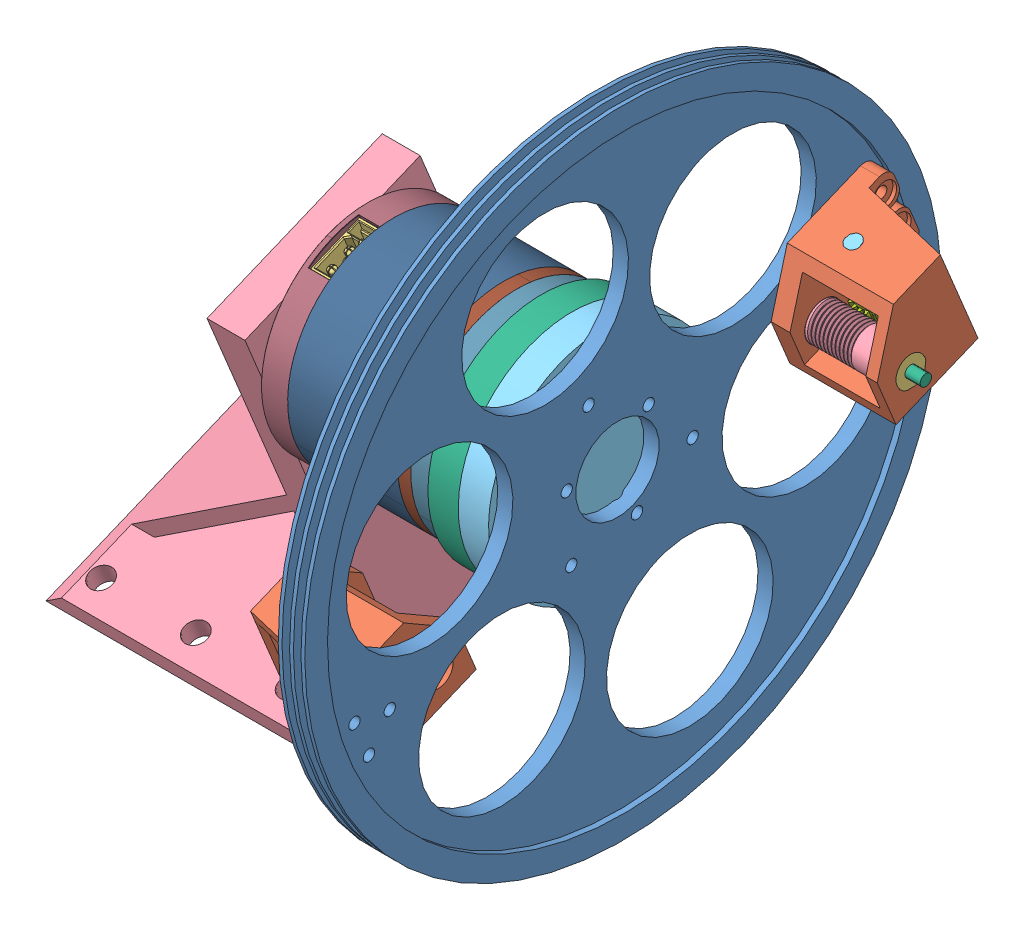
SolidWorks assembly 电机测试组件, configuration 默认. Lengths in mm.
Overall size (174 219.42 219.42).
54 component instances, 24 part files, 15 mates.
Components (placement in the parent):
- 轮组2.0-1: 轮组2.0 [默认] at (56.4404 123.864 309.1516) x (0 -0.381849 0.924225) z (0 0.924225 0.381849) size (168 7.5 168)
- 装配体-1: 装配体 [默认] at (78.4555 112.6983 239.544) x (1 0 0) z (0 0.924225 0.381849) size (32 33.9 26)
  - box - 0-1: box - 0 [默认] at (-1.5151 4.9306 23.8992) size (28 33.9 26)
  - bearing-1: bearing [默认] at (-12.3151 -9.9694 28.8992) x (0 0 1) z (-1 0 0) size (9 9 3)
  - bearing-2: bearing [默认] at (9.2849 -9.9694 28.8992) x (0 -0.428044 -0.903758) z (1 0 0) size (9 9 3)
  - 零件2-1: 零件2 [默认] at (-11.5151 -9.9694 28.8992) x (1 0 0) z (0 -0.101118 0.994874) size (20 9.82 9.8)
  - zhou1-1: zhou1 [默认] at (-5.5151 -0.5694 20.8992) x (1 0 0) z (0 -1 0) size (4 26 4)
  - zhou2-1: zhou2 [默认] at (-14.5151 -9.9694 28.8992) x (0 0 -1) z (1 0 0) size (3 3 30)
  - gear-1: gear [默认] at (-5.5151 -0.5694 31.3992) x (0 0 -1) z (0.913862 -0.406024 0) size (12 10.93 10.93)
  - 1-1: 1 [默认] at (-5.5151 -0.5694 23.8992) x (0.998523 -0.054325 0) z (0 0 1) size (9 9 2.5)
  - 2-1: 2 [默认] at (-5.5151 -0.5694 38.3992) x (0.999989 0.004731 0) z (0 0 1) size (9 9 5.5)
- 装配体-2: 装配体 [默认] at (41.4254 66.8234 350.5792) x (-1 0 0) z (0 0.924225 0.381849) size (32 33.9 26)
  - box - 0-1: box - 0 [默认] at (-1.5151 4.9306 23.8992) size (28 33.9 26)
  - bearing-1: bearing [默认] at (-12.3151 -9.9694 28.8992) x (0 0 1) z (-1 0 0) size (9 9 3)
  - bearing-2: bearing [默认] at (9.2849 -9.9694 28.8992) x (0 -0.428044 -0.903758) z (1 0 0) size (9 9 3)
  - 零件2-1: 零件2 [默认] at (-11.5151 -9.9694 28.8992) x (1 0 0) z (0 -0.101118 0.994874) size (20 9.82 9.8)
  - zhou1-1: zhou1 [默认] at (-5.5151 -0.5694 20.8992) x (1 0 0) z (0 -1 0) size (4 26 4)
  - zhou2-1: zhou2 [默认] at (-14.5151 -9.9694 28.8992) x (0 0 -1) z (1 0 0) size (3 3 30)
  - gear-1: gear [默认] at (-5.5151 -0.5694 31.3992) x (0 0 -1) z (0.913862 -0.406024 0) size (12 10.93 10.93)
  - 1-1: 1 [默认] at (-5.5151 -0.5694 23.8992) x (0.998523 -0.054325 0) z (0 0 1) size (9 9 2.5)
  - 2-1: 2 [默认] at (-5.5151 -0.5694 38.3992) x (0.999989 0.004731 0) z (0 0 1) size (9 9 5.5)
- 达秒 4310 减速电机 3D-1: 达秒 4310 减速电机 3D [默认] at (2.9404 123.864 309.1516) x (0 -0.924225 -0.381849) z (0 -0.381849 0.924225) size (76.5 46 76.5)
  - 达秒 4310 减速电机 3D 20221104.STEP-1: 达秒 4310 减速电机 3D 20221104.STEP [默认] at origin size (76.5 46 76.5)
    - 4310 ________________3D.STEP-1: 4310 ________________3D.STEP [默认] x (-1 0 0) z (0 0 -1) size (76.5 45 76.5)
      - 4310 ____________3D.STEP-1: 4310 ____________3D.STEP [默认] x (-1 0 0) z (0 0 -1) size (55.43 29.4 56)
      - 4310 __________________B.STEP-1: 4310 __________________B.STEP [默认] at (0 32 0) x (-0.5 0 0.866025) z (0.866025 0 0.5) size (56 3.5 56)
      - 4310 ____________B.STEP-1: 4310 ____________B.STEP [默认] at (0 14.5 0) x (0 0 -1) z (0 1 0) size (11 1.5 28.8)
      - 4310 ________B.STEP-1: 4310 ________B.STEP [默认] at (0 -7 0) x (0 0 -1) z (1 0 0) size (56 7 56)
      - 4310 ________________B.STEP-1: 4310 ________________B.STEP [默认] at (0 38 0) x (-1 0 0) z (0 0 1) size (56 5.9 56)
      - M2.5x10 ______________.STEP-1: M2.5x10 ______________.STEP [默认] at (-17.6777 -6.9 -17.6777) x (-0.608335 0 0.79368) z (-0.79368 0 -0.608335) size (5 10 5)
      - M2.5x8 ______________.STEP-1: M2.5x8 ______________.STEP [默认] at (0 37.9 -24.5) x (0.794624 0 0.607102) z (0.607102 0 -0.794624) size (5 7.7 5)
      - M2.5x8 ______________.STEP-2: M2.5x8 ______________.STEP [默认] at (21.2176 37.9 12.25) x (-0.923078 0 0.384613) z (0.384613 0 0.923078) size (5 7.7 5)
      - M2.5x8 ______________.STEP-3: M2.5x8 ______________.STEP [默认] at (-21.2176 37.9 12.25) x (0.128454 0 -0.991715) z (-0.991715 0 -0.128454) size (5 7.7 5)
      - M2.5x5 ______________.STEP-1: M2.5x5 ______________.STEP [默认] at (-24.1621 24.75 -13.95) x (0.497833 -0.092998 -0.862272) z (-0.046499 -0.995666 0.080538) size (5 5 5)
      - M1.6x3 ______________.STEP-1: M1.6x3 ______________.STEP [默认] at (-27.5 6.5 -3.5) x (0 -0.828384 0.56016) z (0 0.56016 0.828384) size (3 3 3)
      - M1.6x3 ______________.STEP-2: M1.6x3 ______________.STEP [默认] at (-27.5 6.5 3.5) x (0 -0.828384 0.56016) z (0 0.56016 0.828384) size (3 3 3)
      - M1.6x3 ______________.STEP-3: M1.6x3 ______________.STEP [默认] at (-27.5 21 -3.5) x (0 -0.828384 0.56016) z (0 0.56016 0.828384) size (3 3 3)
      - M1.6x3 ______________.STEP-4: M1.6x3 ______________.STEP [默认] at (-27.5 21 3.5) x (0 -0.828384 0.56016) z (0 0.56016 0.828384) size (3 3 3)
      - M2.5x10 ______________.STEP-2: M2.5x10 ______________.STEP [默认] at (17.6777 -6.9 -17.6777) x (-0.79368 0 -0.608335) z (0.608335 0 -0.79368) size (5 10 5)
      - M2.5x10 ______________.STEP-3: M2.5x10 ______________.STEP [默认] at (17.6777 -6.9 17.6777) x (0.608335 0 -0.79368) z (0.79368 0 0.608335) size (5 10 5)
      - M2.5x10 ______________.STEP-4: M2.5x10 ______________.STEP [默认] at (-17.6777 -6.9 17.6777) x (0.79368 0 0.608335) z (-0.608335 0 0.79368) size (5 10 5)
      - M2.5x5 ______________.STEP-2: M2.5x5 ______________.STEP [默认] at (24.1621 24.75 -13.95) x (0.497833 -0.092998 0.862272) z (-0.046499 -0.995666 -0.080538) size (5 5 5)
      - M2.5x5 ______________.STEP-3: M2.5x5 ______________.STEP [默认] at (0 24.75 27.9) x (-0.995666 -0.092998 0) z (0.092998 -0.995666 0) size (5 5 5)
      - M2.5x4 ______________.STEP-1: M2.5x4 ______________.STEP [默认] at (-13.435 -1.65 -13.435) size (4.7 5.61 4.7)
      - M2.5x4 ______________.STEP-2: M2.5x4 ______________.STEP [默认] at (13.435 -1.65 -13.435) x (0 0 1) z (-1 0 0) size (4.7 5.61 4.7)
      - M2.5x4 ______________.STEP-3: M2.5x4 ______________.STEP [默认] at (13.435 -1.65 13.435) x (-1 0 0) z (0 0 -1) size (4.7 5.61 4.7)
      - M2.5x4 ______________.STEP-4: M2.5x4 ______________.STEP [默认] at (-13.435 -1.65 13.435) x (0 0 -1) z (1 0 0) size (4.7 5.61 4.7)
    - 4310 __________________3D.STEP-1: 4310 __________________3D.STEP [默认] at (0 20.9 0) x (0.866025 0 -0.5) z (0.5 0 0.866025) size (58.06 5 58.06)
      - 4310 ______________3D.STEP-1: 4310 ______________3D.STEP [默认] at (0 18.1 0) x (-0.5 0 0.866025) z (0.866025 0 0.5) size (42.5 5 42.5)
    - g43_v1_1_220606a.STEP-1: g43_v1_1_220606a.STEP [默认] at (0 -0.15 0) x (0 0 -1) z (0 -1 0) size (49.13 53.2 8)
- 达妙电机底座-1: 达妙电机底座 [默认] at (-4.0596 34.8345 299.4182) x (-1 0 0) z (0 -0.924225 -0.381849) size (76 90 110)
- 转换口-1: 转换口 [默认] at (55.5335 180.0062 330.3957) x (0 -0.381849 0.924225) z (0 -0.924225 -0.381849) size (81.96 16 81.96)
  - 转换口卷筒一侧-1: 转换口卷筒一侧 [默认] at (1.8035 -2.4069 60) size (60 8 60)
  - 转换口电机一侧-1: 转换口电机一侧 [默认] at (1.8035 13.5931 60) x (-0.5 0 -0.866025) z (-0.866025 0 0.5) size (60 8 60)
Mates (geometry in assembly coordinates):
- 同心10: concentric aligned: circle of 轮组2.0-1; circle of 装配体-1/box - 0-1
- 同心11: concentric aligned: circle of 轮组2.0-1; circle of 装配体-1/box - 0-1
- 重合8: coincident anti-aligned: plane of 轮组2.0-1 through (61.9404 123.864 309.1516) normal (1 0 0); plane of 装配体-1/box - 0-1 through (61.9404 136.6693 244.1129) normal (-1 0 0)
- 重合9: coincident anti-aligned: plane of 轮组2.0-1 through (57.9404 123.864 309.1516) normal (-1 0 0); plane of 装配体-2/box - 0-1 through (57.9404 87.0289 364.2621) normal (1 0 0)
- 同心13: concentric anti-aligned: circle of 轮组2.0-1; circle of 装配体-2/box - 0-1
- 同心14: concentric anti-aligned: circle of 轮组2.0-1; circle of 装配体-2/box - 0-1
- 同心15: concentric anti-aligned: circle of 轮组2.0-1; circle of 达秒 4310 减速电机 3D-1/达秒 4310 减速电机 3D 20221104.STEP-1/4310 __________________3D.STEP-1/4310 ______________3D.STEP-1
- 重合11: coincident anti-aligned: plane of 达秒 4310 减速电机 3D-1/达秒 4310 减速电机 3D 20221104.STEP-1/4310 ________________3D.STEP-1/4310 ________B.STEP-1 through (-4.0596 123.864 309.1516) normal (-1 0 0); plane of 达妙电机底座-1 through (-4.0596 53.9269 253.2069) normal (1 0 0)
- 同心16: concentric aligned: circle of 达秒 4310 减速电机 3D-1/达秒 4310 减速电机 3D 20221104.STEP-1/4310 ________________3D.STEP-1/4310 ________B.STEP-1; circle of 达妙电机底座-1
- 同心17: concentric aligned: circle of 达秒 4310 减速电机 3D-1/达秒 4310 减速电机 3D 20221104.STEP-1/4310 ________________3D.STEP-1/4310 ________B.STEP-1; circle of 达妙电机底座-1
- 重合13: coincident anti-aligned: plane of 达秒 4310 减速电机 3D-1/达秒 4310 减速电机 3D 20221104.STEP-1/4310 __________________3D.STEP-1/4310 ______________3D.STEP-1 through (41.9404 122.0502 313.5417) normal (1 0 0); plane of 转换口-1/转换口电机一侧-1 through (41.9404 123.864 309.1516) normal (-1 0 0)
- 同心21: concentric aligned: circle of 达秒 4310 减速电机 3D-1/达秒 4310 减速电机 3D 20221104.STEP-1/4310 __________________3D.STEP-1/4310 ______________3D.STEP-1; circle of 转换口-1/转换口电机一侧-1
- 同心22: concentric aligned: cylinder of 达秒 4310 减速电机 3D-1/达秒 4310 减速电机 3D 20221104.STEP-1/4310 __________________3D.STEP-1/4310 ______________3D.STEP-1; cylinder of 转换口-1/转换口电机一侧-1 through (34.9404 125.6382 322.5345) axis (1 0 0) radius 1.6
- 重合14: coincident aligned: circle of 轮组2.0-1; circle of 转换口-1/转换口卷筒一侧-1
- 同心23: concentric anti-aligned: circle of 轮组2.0-1; circle of 转换口-1/转换口卷筒一侧-1
